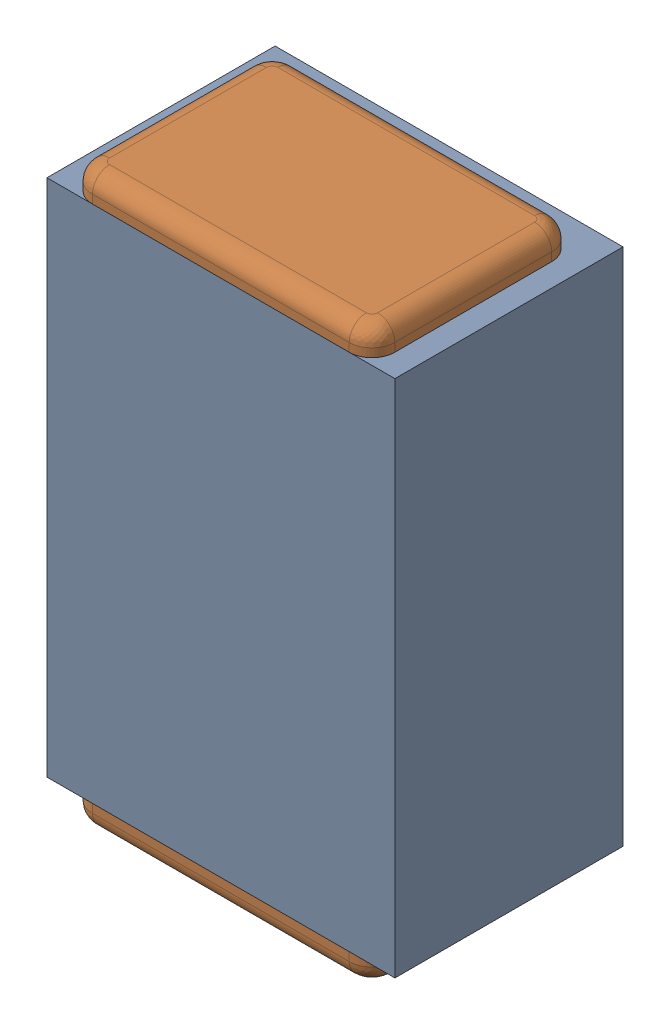
SolidWorks assembly C37, configuration Default. Lengths in mm.
Overall size (0.61 1 0.4).
3 component instances, 2 part files, 0 mates.
Components (placement in the parent):
- 1088881848-1: 1088881848 [Default] at (9.325 28.875 -2.044) size (0.61 0.91 0.4)
  - Extruded-1-1: Extruded-1 [Default] at origin size (0.61 0.91 0.4)
- C0402-1: C0402 [Default] at (9.3249 28.8749 -1.644) x (0 -1 0) z (1 0 0) size (1 0.36 0.54)
